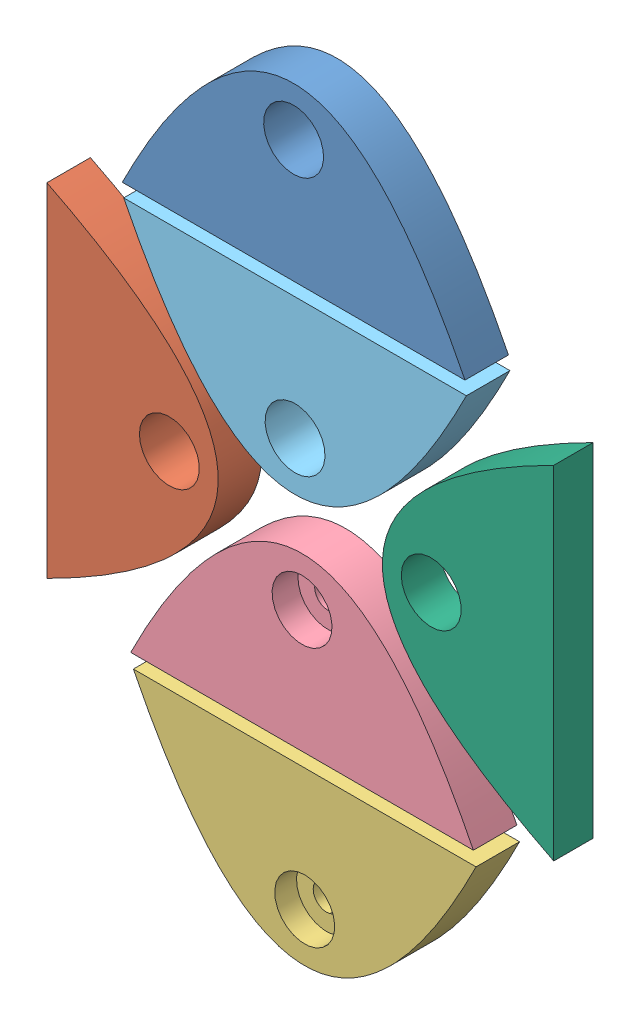
SolidWorks assembly final_parts, configuration Default. Lengths in mm.
Overall size (986.86 885.58 452.4).
6 component instances, 6 part files, 8 mates.
Components (placement in the parent):
- cut_1-1: cut_1 [Default] at (317.3386 272.6401 -249.2) x (-1 0 0) z (0 1 0) size (400 50.8 200)
- cut_2-1: cut_2 [Default] at (29.2958 28.1628 -198.4) x (0 1 0) z (1 0 0) size (400 101.6 400)
- cut_3-1: cut_3 [Default] at (330.2776 -212.9357 -147.6) x (1 0 0) z (0 -1 0) size (400 152.4 400)
- cut_4-1: cut_4 [Default] at (327.164 -197.6957 147.6) x (1 0 0) z (0 1 0) size (400 203.2 400)
- cut_5-1: cut_5 [Default] at (319.0114 257.6981 -46) x (1 0 0) z (0 -1 0) size (400 254 400)
- cut_6-1: cut_6 [Default] at (616.1603 33.5278 0) x (0 -1 0) z (-1 0 0) size (400 300 400)
Mates (geometry in assembly coordinates):
- Coincident3: coincident aligned: plane of cut_2-1 through (229.2958 280.419 0) normal (0 0 -1); plane of cut_6-1 through (416.1603 33.5278 0) normal (0 0 -1)
- Coincident4: coincident aligned: plane of cut_1-1 through (60.5403 572.6401 0) normal (0 0 -1); plane of cut_6-1 through (416.1603 33.5278 0) normal (0 0 -1)
- Coincident5: coincident aligned: plane of cut_1-1 through (60.5403 572.6401 0) normal (0 0 -1); plane of cut_5-1 through (569.8052 57.6981 0) normal (0 0 -1)
- Coincident6: coincident aligned: plane of cut_3-1 through (579.6091 -412.9357 0) normal (0 0 -1); plane of cut_6-1 through (416.1603 33.5278 0) normal (0 0 -1)
- Coincident8: coincident aligned: plane of cut_2-1 through (229.2958 280.419 0) normal (0 0 -1); plane of cut_4-1 through (572.5958 2.3043 0) normal (0 0 -1)
- Coincident10: coincident anti-aligned: plane of cut_4-1 through (572.5958 2.3043 0) normal (0 0 -1); plane of assembly through (0 0 0) normal (0 0 1)
- Distance1: distance = 15.24 mm: line of cut_3-1 through (530.2776 -212.9357 50.8) axis (-1 0 0); line of cut_4-1 through (127.164 -197.6957 50.8) axis (1 0 0)
- Distance2: distance = 14.942 mm: line of cut_1-1 through (117.3386 272.6401 50.8) axis (1 0 0); line of cut_5-1 through (519.0114 257.6981 50.8) axis (-1 0 0)
